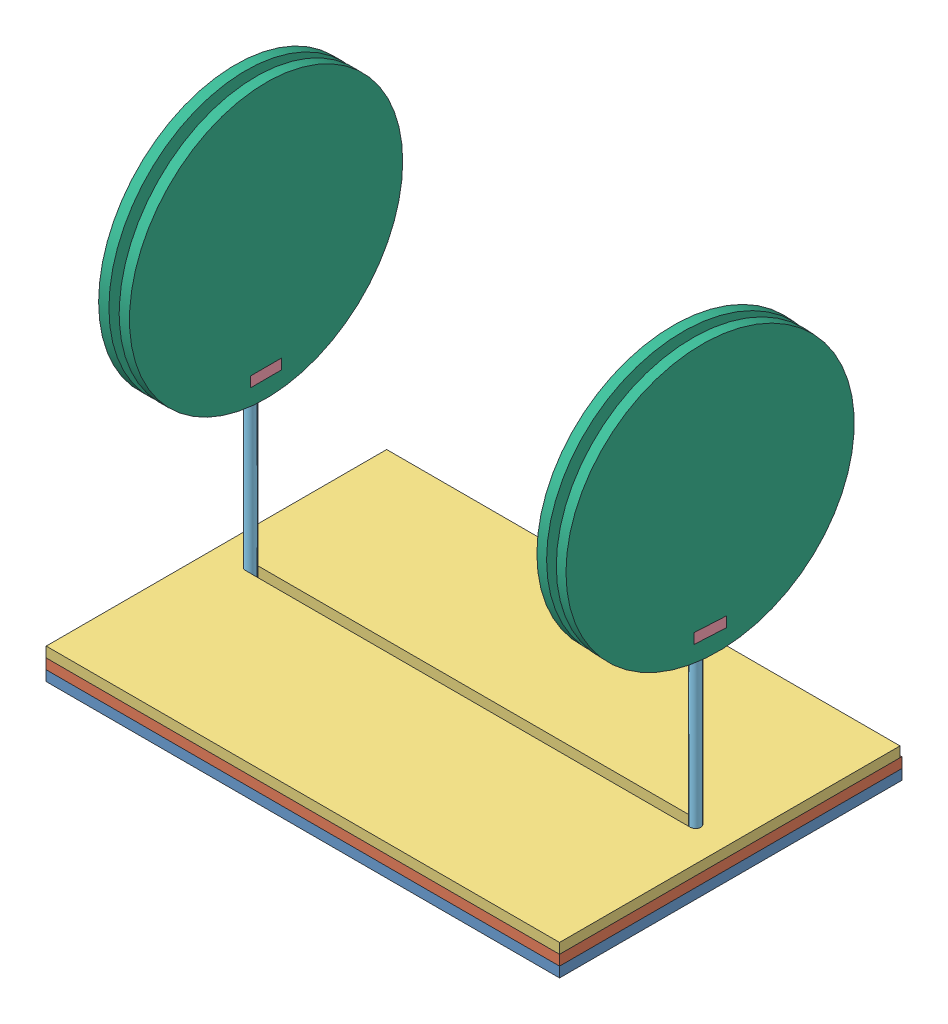
SolidWorks assembly fullmodel, configuration Default. Lengths in mm.
Overall size (150 134 100).
13 component instances, 7 part files, 34 mates.
Components (placement in the parent):
- base1-1: base1 [Default] at (-5.3198 58.126 170.5863) size (150 3 100)
- base2-1: base2 [Default] at (-5.3198 61.126 170.5863) size (150 3 100)
- base3-1: base3 [Default] at (-5.3198 64.126 170.5863) size (150 3 99.48)
- joiner-1: joiner [Default] at (0.1894 120.126 125.3569) x (0 -1 0) z (0.002049 0 0.999998) size (3 9 9)
- slider-2: slider [Default] at (4.6802 64.126 120.8477) x (-0.002049 0 -0.999998) z (0.999998 0 -0.002049) size (12 62 8)
- slider-3: slider [Default] at (134.6802 64.126 120.8477) x (-0.054358 0 0.998521) z (-0.998521 0 -0.054358) size (12 62 8)
- joiner-2: joiner [Default] at (130.4315 117.126 116.1098) x (0 1 0) z (0.054358 0 -0.998521) size (3 9 9)
- coilcase-1: coilcase [Default] at (9.1802 152.126 120.8385) x (0.002049 0 0.999998) z (-0.999998 0 0.002049) size (80 80 3)
- coilcase-2: coilcase [Default] at (130.1868 152.126 120.6031) x (0.054358 0 -0.998521) z (0.998521 0 0.054358) size (80 80 3)
- coilcase-3: coilcase [Default] at (136.178 152.126 120.9293) x (0.054358 0 -0.998521) z (0.998521 0 0.054358) size (80 80 3)
- coilcase-4: coilcase [Default] at (0.1802 152.126 120.8569) x (-0.002049 0 -0.999998) z (0.999998 0 -0.002049) size (80 80 3)
- coil support-1: coil support [Default] at (3.1802 152.126 120.8508) x (-0.002049 0 -0.999998) z (0.999998 0 -0.002049) size (49.96 50 3)
- coil support-2: coil support [Default] at (133.1824 152.126 120.7662) x (0.054358 0 -0.998521) z (0.998521 0 0.054358) size (49.96 50 3)
Mates (geometry in assembly coordinates):
- Coincident1: coincident anti-aligned: plane of base1-1 through (-5.3198 61.126 170.5863) normal (0 1 0); plane of base2-1 through (-5.3198 61.126 170.5863) normal (0 -1 0)
- Coincident2: coincident: point of base1-1; point of base2-1
- Coincident3: coincident anti-aligned: plane of base2-1 through (-5.3198 64.126 170.5863) normal (0 1 0); plane of base3-1 through (-5.3198 64.126 170.5863) normal (0 -1 0)
- Coincident4: coincident: point of base2-1; point of base3-1
- Slot1: slot aligned: cylinder of slider-2 through (4.6802 114.126 120.8477) axis (0 -1 0) radius 1.5; cylinder of base3-1 through (4.6802 67.126 120.8477) axis (0 -1 0) radius 1.5; cylinder of base3-1 through (134.6802 67.126 120.8477) axis (0 -1 0) radius 1.5
- Coincident5: coincident anti-aligned: line of base2-1 through (-5.3198 64.126 170.5863) axis (0 0 -1); line of base3-1 through (-5.3198 64.126 71.1092) axis (0 0 1)
- Coincident6: coincident anti-aligned: plane of base3-1 through (-5.3198 64.126 170.5863) normal (0 -1 0); plane of slider-2 through (4.6802 64.126 120.8477) normal (0 1 0)
- Coincident7: coincident anti-aligned: plane of joiner-1 through (9.1894 120.126 125.3385) normal (0 1 0); plane of slider-2 through (2.1802 120.126 120.8529) normal (0 -1 0)
- Coincident8: coincident anti-aligned: line of joiner-1 through (9.1894 120.126 125.3385) axis (-0.999998 0 0.002049); line of slider-2 through (3.1894 120.126 125.3508) axis (0.999998 0 -0.002049)
- Distance1: distance = 3 mm aligned: plane of joiner-1 through (9.1894 120.126 125.3385) normal (0.999998 0 -0.002049); plane of slider-2 through (6.1802 64.126 120.8447) normal (0.999998 0 -0.002049)
- Coincident10: coincident anti-aligned: line of base1-1 through (-5.3198 61.126 70.5863) axis (0 0 1); line of base2-1 through (-5.3198 61.126 170.5863) axis (0 0 -1)
- Slot2: slot aligned: cylinder of slider-3 through (134.6802 114.126 120.8477) axis (0 -1 0) radius 1.5; cylinder of base3-1 through (134.6802 67.126 120.8477) axis (0 -1 0) radius 1.5; cylinder of base3-1 through (4.6802 67.126 120.8477) axis (0 -1 0) radius 1.5
- Coincident11: coincident anti-aligned: plane of base3-1 through (-5.3198 64.126 170.5863) normal (0 -1 0); plane of slider-3 through (134.6802 64.126 120.8477) normal (0 1 0)
- Coincident12: coincident anti-aligned: plane of slider-3 through (137.1765 120.126 120.9836) normal (0 -1 0); plane of joiner-2 through (139.4181 120.126 116.599) normal (0 1 0)
- Coincident13: coincident aligned: line of slider-3 through (136.4226 120.126 116.4359) axis (-0.998521 0 -0.054358); line of joiner-2 through (139.4181 120.126 116.599) axis (-0.998521 0 -0.054358)
- Distance2: distance = 3 mm aligned: plane of joiner-2 through (130.4315 117.126 116.1098) normal (-0.998521 0 -0.054358); plane of slider-3 through (133.1824 64.126 120.7662) normal (-0.998521 0 -0.054358)
- Coincident16: coincident aligned: plane of joiner-2 through (130.4315 117.126 116.1098) normal (-0.998521 0 -0.054358); plane of coilcase-2 through (130.1868 152.126 120.6031) normal (-0.998521 0 -0.054358)
- Coincident17: coincident aligned: line of joiner-2 through (130.4315 120.126 116.1098) axis (-0.054358 0 0.998521); line of coilcase-2 through (130.4315 120.126 116.1098) axis (-0.054358 0 0.998521)
- Coincident18: coincident anti-aligned: line of joiner-2 through (129.9422 120.126 125.0965) axis (0 -1 0); line of coilcase-2 through (129.9422 117.126 125.0965) axis (0 1 0)
- Coincident20: coincident aligned: plane of joiner-2 through (139.4181 117.126 116.599) normal (0.998521 0 0.054358); plane of coilcase-3 through (139.1735 152.126 121.0923) normal (0.998521 0 0.054358)
- Coincident21: coincident anti-aligned: line of joiner-2 through (138.9289 117.126 125.5857) axis (0.054358 0 -0.998521); line of coilcase-3 through (139.4181 117.126 116.599) axis (-0.054358 0 0.998521)
- Coincident22: coincident anti-aligned: line of joiner-2 through (138.9289 120.126 125.5857) axis (0 -1 0); line of coilcase-3 through (138.9289 117.126 125.5857) axis (0 1 0)
- Coincident23: coincident aligned: plane of joiner-1 through (9.1894 120.126 125.3385) normal (0.999998 0 -0.002049); plane of coilcase-1 through (9.1802 152.126 120.8385) normal (0.999998 0 -0.002049)
- Coincident24: coincident anti-aligned: line of joiner-1 through (9.1894 120.126 125.3385) axis (0 -1 0); line of coilcase-1 through (9.1894 117.126 125.3385) axis (0 1 0)
- Coincident25: coincident anti-aligned: line of joiner-1 through (9.171 120.126 116.3385) axis (0.002049 0 0.999998); line of coilcase-1 through (9.1894 120.126 125.3385) axis (-0.002049 0 -0.999998)
- Coincident26: coincident aligned: plane of joiner-1 through (0.1894 120.126 125.3569) normal (-0.999998 0 0.002049); plane of coilcase-4 through (0.1802 152.126 120.8569) normal (-0.999998 0 0.002049)
- Coincident27: coincident anti-aligned: line of joiner-1 through (0.1894 117.126 125.3569) axis (-0.002049 0 -0.999998); line of coilcase-4 through (0.171 117.126 116.357) axis (0.002049 0 0.999998)
- Coincident28: coincident anti-aligned: line of joiner-1 through (0.1894 120.126 125.3569) axis (0 -1 0); line of coilcase-4 through (0.1894 117.126 125.3569) axis (0 1 0)
- Coincident30: coincident anti-aligned: plane of coilcase-4 through (3.1802 152.126 120.8508) normal (0.999998 0 -0.002049); plane of coil support-1 through (3.1802 152.126 120.8508) normal (-0.999998 0 0.002049)
- Coincident31: coincident anti-aligned: plane of coilcase-2 through (133.1824 152.126 120.7662) normal (0.998521 0 0.054358); plane of coil support-2 through (133.1824 152.126 120.7662) normal (-0.998521 0 -0.054358)
- Parallel2: parallel anti-aligned: plane of base3-1 through (-5.3198 67.126 170.5863) normal (0 1 0); plane of coil support-2 through (136.178 153.126 120.9293) normal (0 -1 0)
- Concentric4: concentric aligned: circle of coilcase-2; circle of coil support-2
- Parallel3: parallel anti-aligned: plane of base3-1 through (-5.3198 67.126 170.5863) normal (0 1 0); plane of coil support-1 through (6.1802 153.126 120.8447) normal (0 -1 0)
- Concentric5: concentric aligned: circle of coilcase-4; circle of coil support-1
